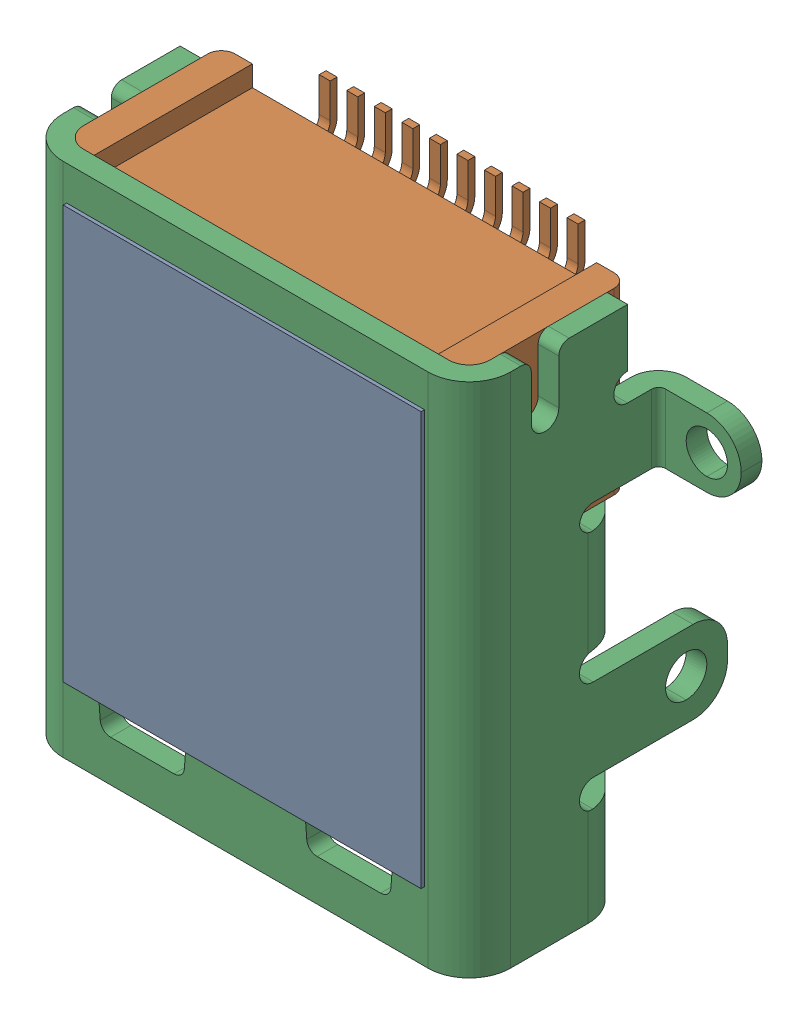
SolidWorks assembly HDMI-101L, configuration Défaut. Lengths in mm.
Overall size (8.9 7.5 3.8).
2 component instances, 1 part files, 0 mates.
Components (placement in the parent):
- 3767e841d01a442b9ab53d6dc2195e1f.step-1: 3767e841d01a442b9ab53d6dc2195e1f.step [Défaut] at (2.9312 -5.6922 1.6) size (8.9 7.5 3.8)
  - COMPOUND.step_1809-1: COMPOUND.step_1809 [Défaut] at origin size (8.9 7.5 3.8)
